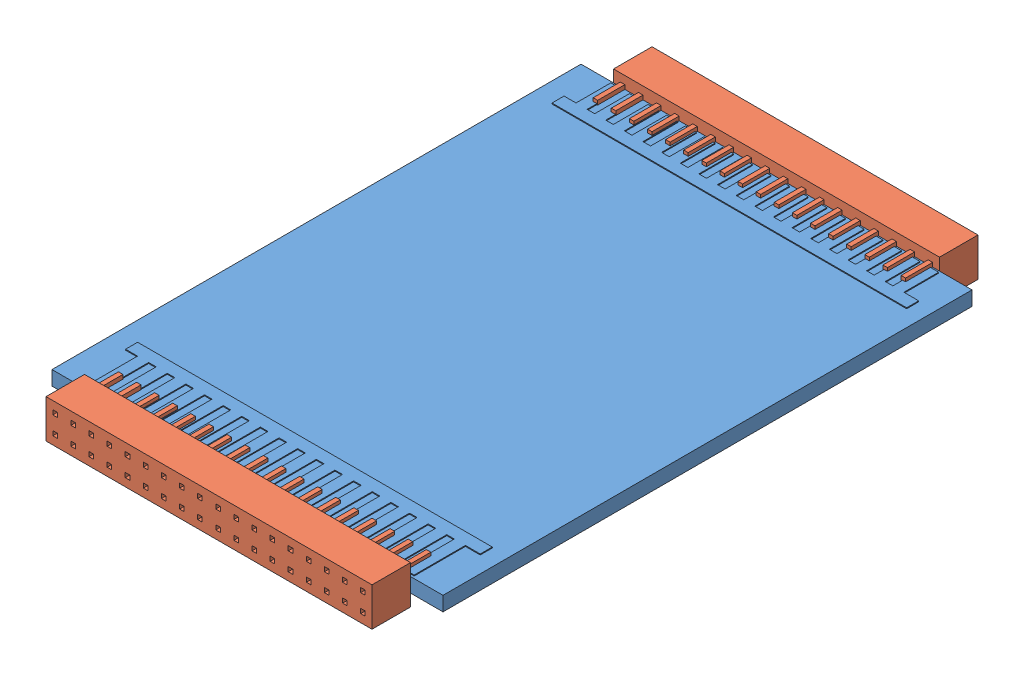
SolidWorks assembly H8500-amp.revB, configuration Default. Lengths in mm.
Overall size (43.18 4.25 66.92).
3 component instances, 2 part files, 0 mates.
Components (placement in the parent):
- H8500-amp.revB-1: H8500-amp.revB [Default] at origin size (43.18 1.69 58.42)
- connector.2mm.36-pin.female-1: connector.2mm.36-pin.female [Default] at (3.59 2.9187 0) x (1 0 0) z (0 -1 0) size (36 7.25 4.25)
- connector.2mm.36-pin.female-2: connector.2mm.36-pin.female [Default] at (39.59 2.92 -58.42) x (-1 0 0) z (0 -1 0) size (36 7.25 4.25)
